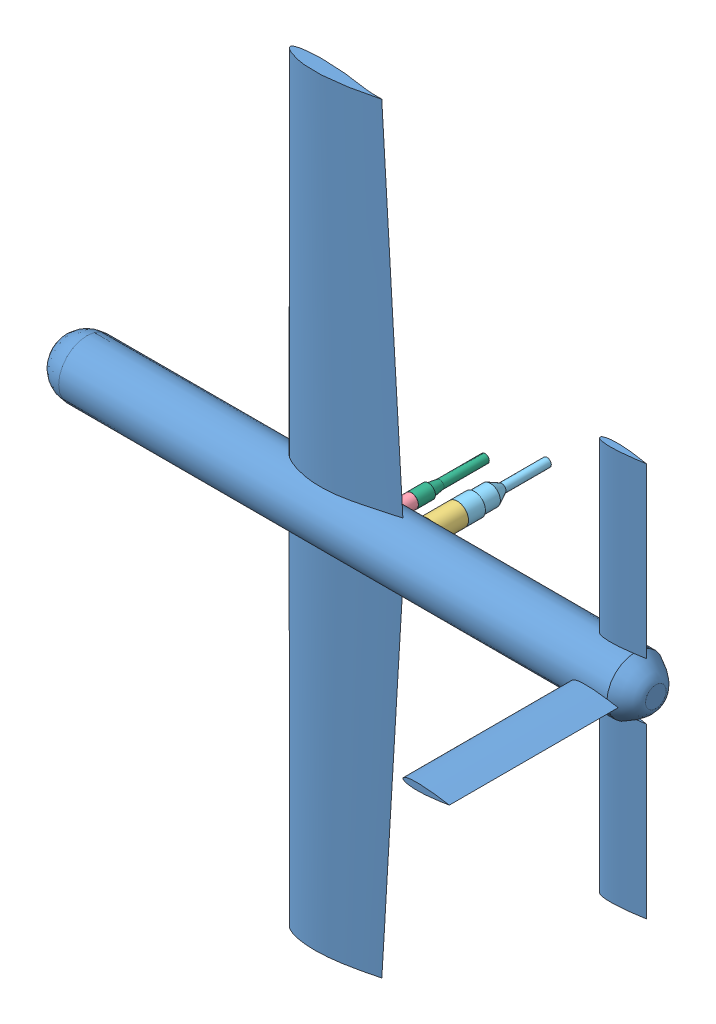
SolidWorks assembly Assem1, configuration Default. Lengths in mm.
Overall size (670 854.48 388.03).
8 component instances, 8 part files, 14 mates.
Components (placement in the parent):
- Buoyancy Model-1: Buoyancy Model [Default] at origin size (670 854.48 252.9)
- Bridle_Compact-1: Bridle_Compact [Default] at (22.1742 0 -25.4) x (1 0 0) z (0 0 -1) size (44.45 38.1 66.87)
- MCBH12-F-1: MCBH12-F [Default] at (121.1072 0 -25.4) x (0 0 1) z (-1 0 0) size (40.89 24.89 24.89)
- MCBH8-F-1: MCBH8-F [Default] at (82.4992 0 -25.4) x (0 0 1) z (-1 0 0) size (27.94 19.05 21.59)
- MCIL12M-1: MCIL12M [Default] at (121.1072 0 -66.294) x (0 0 1) z (-1 0 0) size (100.58 24.89 24.89)
- MCIL8M-1: MCIL8M [Default] at (82.4992 0 -53.34) x (0 0 1) z (-1 0 0) size (82.55 15.75 15.75)
- 92510A817_ALUM UNTHRD SPACER-1: 92510A817_ALUM UNTHRD SPACER [92510A817] at (19.1742 -0.3175 -79.568) x (1 0 0) z (0 1 0) size (25.4 25.4 9.53)
- 92735A500_CLEVIS PIN WITH RETAINING RING GROOVE-1: 92735A500_CLEVIS PIN WITH RETAINING RING GROOVE [92735A500] at (19.1742 -3.175 -79.568) x (1 0 0) z (0 1 0) size (20.32 18.8 29.46)
Mates (geometry in assembly coordinates):
- Coincident1: coordinate: point of Buoyancy Model-1
- Coincident2: coincident anti-aligned: plane of Buoyancy Model-1 through (-6.4008 -427.1928 -25.4) normal (0 0 -1); plane of Bridle_Compact-1 through (22.1742 0 -25.4) normal (0 0 1)
- Distance1: distance = 6.35 mm anti-aligned: plane of Bridle_Compact-1 through (-0.0508 19.05 -31.75) normal (-1 0 0); plane of Buoyancy Model-1 through (-6.4008 -427.1928 -58.9092) normal (1 0 0)
- Coincident3: coincident anti-aligned: plane of Bridle_Compact-1 through (22.1742 0 -25.4) normal (0 -1 0)
- ProfileCenter1: profile center anti-aligned: circle of MCIL8M-1; circle of MCBH8-F-1
- ProfileCenter2: profile center anti-aligned: plane of MCIL12M-1 through (121.1072 12.446 -66.294) normal (0 0 1); circle of MCBH12-F-1
- Coincident4: coincident anti-aligned: plane of Buoyancy Model-1 through (-6.4008 -427.1928 -25.4) normal (0 0 -1); plane of MCBH12-F-1 through (121.1072 6.35 -25.4) normal (0 0 1)
- Coincident5: coincident anti-aligned: plane of Buoyancy Model-1 through (-6.4008 -427.1928 -25.4) normal (0 0 -1); plane of MCBH8-F-1 through (82.4992 5.5563 -25.4) normal (0 0 1)
- Coincident6: coincident aligned: plane of MCBH12-F-1 through (121.1072 0 -25.4) normal (0 1 0)
- Coincident7: coincident aligned: plane of MCBH8-F-1 through (82.4992 0 -25.4) normal (0 1 0)
- Distance2: distance = 88.9 mm anti-aligned: plane of MCBH8-F-1 through (82.4992 0 -25.4) normal (-1 0 0); plane of Buoyancy Model-1 through (-6.4008 -427.1928 -58.9092) normal (1 0 0)
- Distance3: distance = 127.508 mm anti-aligned: plane of MCBH12-F-1 through (121.1072 0 -25.4) normal (-1 0 0); plane of Buoyancy Model-1 through (-6.4008 -427.1928 -58.9092) normal (1 0 0)
- ProfileCenter3: profile center anti-aligned: circle of 92510A817_ALUM UNTHRD SPACER-1; circle of Bridle_Compact-1
- ProfileCenter4: profile center anti-aligned: circle of 92735A500_CLEVIS PIN WITH RETAINING RING GROOVE-1; circle of Bridle_Compact-1
